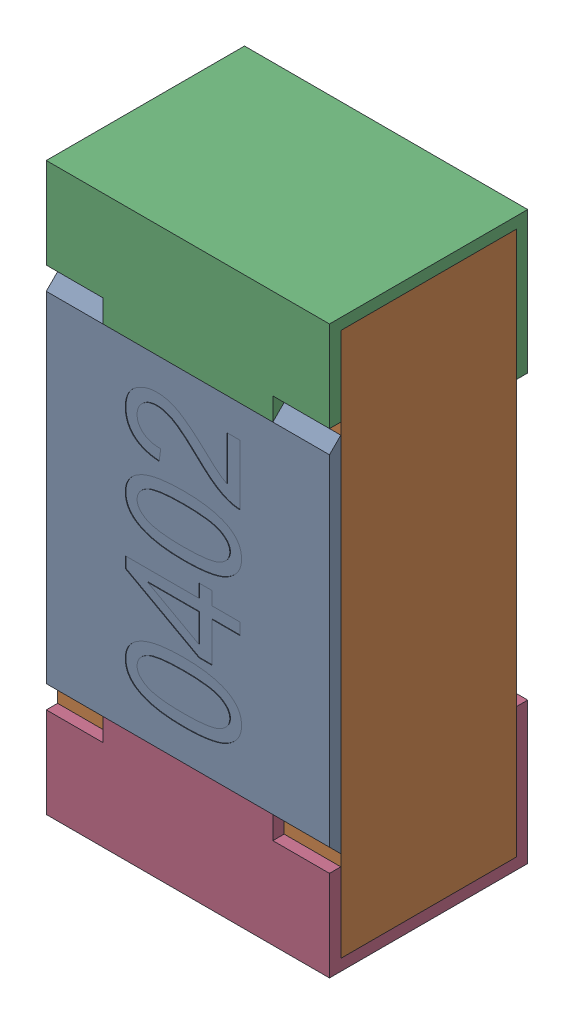
SolidWorks assembly R38, configuration Standard. Lengths in mm.
Overall size (0.5 1 0.35).
5 component instances, 4 part files, 0 mates.
Components (placement in the parent):
- R38-subassembly-1-1: R38-subassembly-1 [Standard] at (-4.8 -3.5999 0) x (0 1 0) z (0 0 1) size (1 0.5 0.35)
  - User Library-R_0402-1: User Library-R_0402 [Standard] at origin size (0.64 0.5 0.02)
  - User Library-R_0402-1-1: User Library-R_0402-1 [Standard] at origin size (0.96 0.5 0.31)
  - User Library-R_0402-2-1: User Library-R_0402-2 [Standard] at origin size (0.25 0.5 0.35)
  - User Library-R_0402-3-1: User Library-R_0402-3 [Standard] at origin size (0.25 0.5 0.35)
